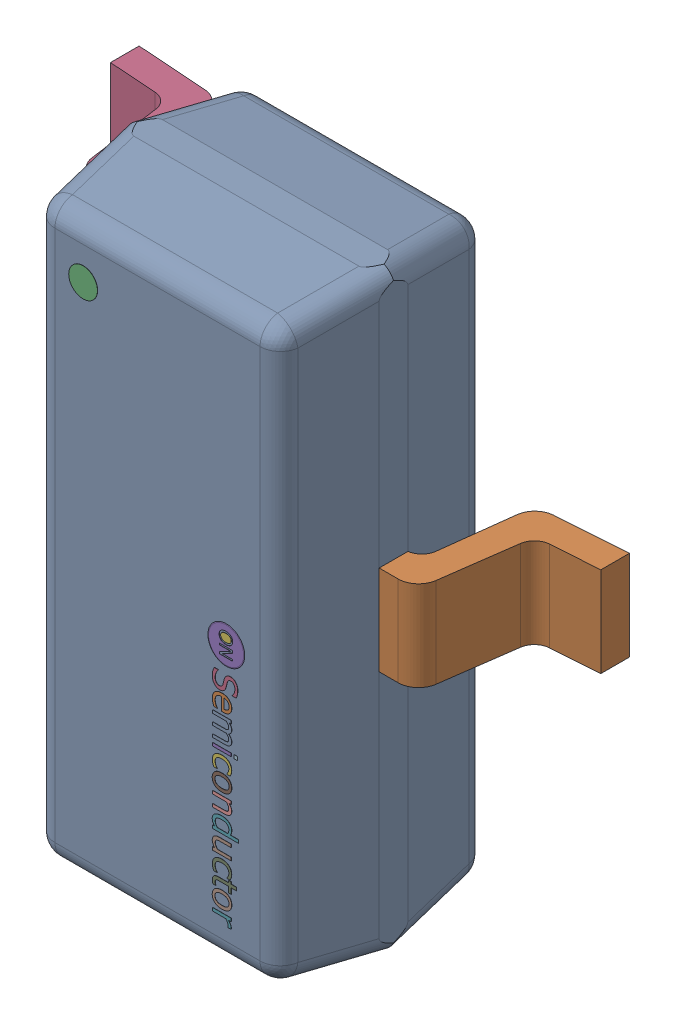
SolidWorks assembly Q1.step, configuration Default. Lengths in mm.
Overall size (2.4 2.9 1.11).
5 component instances, 4 part files, 0 mates.
Components (placement in the parent):
- IC_ON_Semiconductor_NUD3112LT1G_eec.step-1: IC_ON_Semiconductor_NUD3112LT1G_eec.step [Default] at (17.919 31.181 0) size (2.4 2.9 1.11)
  - 1-5.step-1: 1-5.step [Default] at (0 0 0.1) x (0 1 0) z (0 0 1) size (2.9 1.3 1.01)
  - 2-6.step-1: 2-6.step [Default] x (-1 0 0) z (0 1 0) size (2.4 0.68 2.34)
  - ON Semi Logo - withoutPN.step-1: ON Semi Logo - withoutPN.step [Default] at (-0.2581 -0.9018 1.011) x (-1 0 0) z (0 0 1) size (0.19 0.19 0.1)
  - ON Semi Logo - withoutPN - Copy.step-1: ON Semi Logo - withoutPN - Copy.step [Default] at (-0.2645 -0.8914 1.011) x (-1 0 0) z (0 0 1) size (0.83 2.45 0.1)
